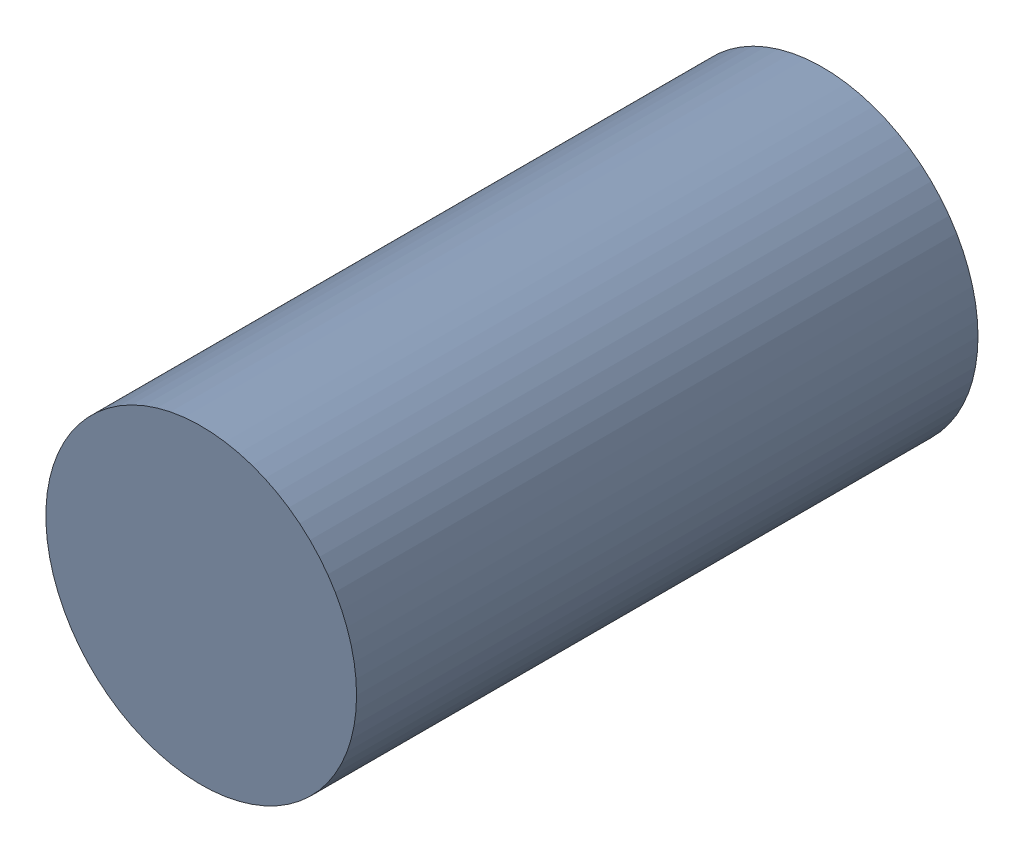
SolidWorks assembly MH12_1.step, configuration Default. Lengths in mm.
Overall size (1 1 2).
2 component instances, 1 part files, 0 mates.
Components (placement in the parent):
- 9228463120_1.step-3: 9228463120_1.step [Default] at (433.1523 311.7064 -1.5) size (1 1 2)
  - Cylinder_1.step-26: Cylinder_1.step [Default] at origin size (1 1 2)
